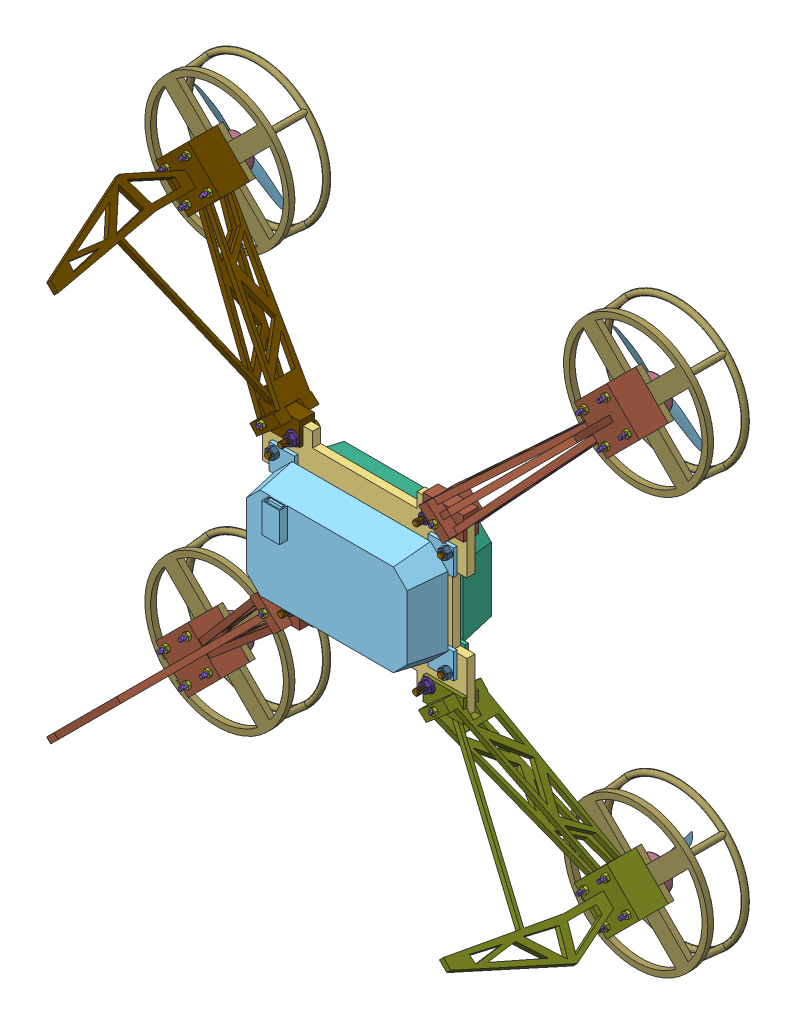
SolidWorks assembly ds2, configuration Default. Lengths in mm.
Overall size (539.99 537.83 191.42).
99 component instances, 18 part files, 83 mates.
Components (placement in the parent):
- battery-1: battery [Default] at (18.8177 46.9585 54.9424) size (80 50 20)
- casing-1: casing [Default] at (19.625 49.8237 64.9424) size (96 66 13)
- frame-1: frame [Default] at (21.8083 42.8166 57.9424) x (0 1 0) z (0 0 1) size (147.04 177.04 7)
- microelectronics-1: microelectronics [Default] at (21.2423 49.2552 77.9424) size (63.91 64.04 8)
- shell-1: shell [Default] at (46.8083 62.2846 67.9424) size (159.85 99.85 47)
- shell up-1: shell up [Default] at (-3.1917 62.2846 54.9424) x (-1 0 0) z (0 0 -1) size (159.85 99.85 36)
- casing-3: casing [Default] at (19.625 35.8094 57.9424) x (1 0 0) z (0 0 -1) size (96 66 13)
- M3 Nut-1: M3 Nut [Default] at (67.2879 12.3183 79.1424) x (0.927238 -0.374472 0) z (0 0 1) size (5.5 6.35 2.74)
- M3 X 16mm Screw-1: M3 X 16mm Screw [Default] at (67.3083 12.3166 71.5424) x (0 0 1) z (-0.987325 -0.158711 0) size (48.24 5.6 5.6)
- M3 Nut-2: M3 Nut [Default] at (-23.6713 12.3183 79.1424) x (-0.927238 -0.374472 0) z (0 0 1) size (5.5 6.35 2.74)
- M3 X 16mm Screw-2: M3 X 16mm Screw [Default] at (-23.6917 12.3166 71.5424) x (0 0 1) z (0.987325 -0.158711 0) size (48.24 5.6 5.6)
- M3 Nut-3: M3 Nut [Default] at (67.2879 73.3148 79.1424) x (0.927238 0.374472 0) z (0 0 1) size (5.5 6.35 2.74)
- M3 X 16mm Screw-3: M3 X 16mm Screw [Default] at (67.3083 73.3166 71.5424) x (0 0 1) z (-0.987325 0.158711 0) size (48.24 5.6 5.6)
- M3 Nut-4: M3 Nut [Default] at (-23.6713 73.3148 79.1424) x (-0.927238 0.374472 0) z (0 0 1) size (5.5 6.35 2.74)
- M3 X 16mm Screw-4: M3 X 16mm Screw [Default] at (-23.6917 73.3166 71.5424) x (0 0 1) z (0.987325 0.158711 0) size (48.24 5.6 5.6)
- heavy hex flange screw_am-1: heavy hex flange screw_am [B18.2.3.9M - Heavy hex flange screw, M5 x 0.8 x 20 --20S] at (-53.1917 87.8166 49.1424) x (0 0 1) z (-0.923728 -0.383049 0) size (25.8 11.8 11.8)
- hex nut style 1_am-1: hex nut style 1_am [B18.2.4.1M - Hex nut, Style 1,  M5 x 0.8 --D-N] at (-53.1917 87.8166 67.9424) x (1 0 0) z (0 0 -1) size (8 9.24 4.7)
- heavy hex flange screw_am-2: heavy hex flange screw_am [B18.2.3.9M - Heavy hex flange screw, M5 x 0.8 x 20 --20S] at (96.8083 87.8166 49.1424) x (0 0 1) z (-0.923728 0.383049 0) size (25.8 11.8 11.8)
- hex nut style 1_am-2: hex nut style 1_am [B18.2.4.1M - Hex nut, Style 1,  M5 x 0.8 --D-N] at (96.8083 87.8166 72.6424) x (-1 0 0) z (0 0 1) size (8 9.24 4.7)
- heavy hex flange screw_am-3: heavy hex flange screw_am [B18.2.3.9M - Heavy hex flange screw, M5 x 0.8 x 20 --20S] at (-53.1917 -2.1834 49.1424) x (0 0 1) z (0.923728 -0.383049 0) size (25.8 11.8 11.8)
- hex nut style 1_am-3: hex nut style 1_am [B18.2.4.1M - Hex nut, Style 1,  M5 x 0.8 --D-N] at (-53.1917 -2.1834 72.6424) size (8 9.24 4.7)
- heavy hex flange screw_am-4: heavy hex flange screw_am [B18.2.3.9M - Heavy hex flange screw, M5 x 0.8 x 20 --20S] at (96.8083 -2.1834 49.1424) x (0 0 1) z (0.923728 0.383049 0) size (25.8 11.8 11.8)
- hex nut style 1_am-4: hex nut style 1_am [B18.2.4.1M - Hex nut, Style 1,  M5 x 0.8 --D-N] at (96.8083 -2.1834 67.9424) x (-1 0 0) z (0 0 -1) size (8 9.24 4.7)
- arms-2: arms [Default] at (-49.2115 -25.7033 61.4424) size (156.23 150.15 153.92)
- propellers-1: propellers [Default] at (-143.0026 -204.8079 -99.2159) x (0.707107 0.707107 0) z (0 0 1) size (125.2 125.2 37.5)
  - propeller shield-1: propeller shield [Default] at (35.7674 59.3211 105.7949) size (125.2 125.2 37.5)
  - motor-1: motor [Default] at (35.7674 59.3211 90.0261) x (1 0 0) z (0 1 0) size (28.43 25 28.43)
  - aeronaut_cam_carbon_light_13x5.step-1: aeronaut_cam_carbon_light_13x5.step [Default] at (35.7659 59.3206 89.8554) x (0.983894 0.178751 0) z (0 0 1) size (100.1 9.42 3.24)
  - M3 Nut-1: M3 Nut [Default] at (35.7674 59.3211 87.1925) x (0.707107 0.707107 0) z (0 0 1) size (5.5 6.35 2.74)
  - tip-2: tip [Default] at (35.7674 59.3211 82.6885) x (-0.916245 0.400617 0) z (-0.400617 -0.916245 0) size (4.73 7 4.73)
- arms-6: arms [Default] at (92.8281 111.3364 61.4424) x (-1 0 0) z (0 0 1) size (156.23 150.15 153.92)
- propellers-4: propellers [Default] at (136.0365 206.5484 -99.2159) x (0.707107 -0.707107 0) z (0 0 1) size (125.2 125.2 37.5)
  - propeller shield-1: propeller shield [Default] at (35.7674 59.3211 105.7949) size (125.2 125.2 37.5)
  - motor-1: motor [Default] at (35.7674 59.3211 90.0261) x (1 0 0) z (0 1 0) size (28.43 25 28.43)
  - aeronaut_cam_carbon_light_13x5.step-1: aeronaut_cam_carbon_light_13x5.step [Default] at (35.7659 59.3206 89.8554) x (0.983894 0.178751 0) z (0 0 1) size (100.1 9.42 3.24)
  - M3 Nut-1: M3 Nut [Default] at (35.7674 59.3211 87.1925) x (0.707107 0.707107 0) z (0 0 1) size (5.5 6.35 2.74)
  - tip-2: tip [Default] at (35.7674 59.3211 82.6885) x (-0.916245 0.400617 0) z (-0.400617 -0.916245 0) size (4.73 7 4.73)
- M3 X 16mm Screw-5: M3 X 16mm Screw [Default] at (-51.8729 -27.4903 71.5424) x (0 0 1) z (-1 0 0) size (48.24 5.6 5.6)
- M3 Nut-5: M3 Nut [Default] at (-51.8729 -27.4903 79.1424) size (5.5 6.35 2.74)
- M3 Nut-6: M3 Nut [Default] at (-159.6576 -119.1854 37.7789) size (5.5 6.35 2.74)
- M3 X 16mm Screw-6: M3 X 16mm Screw [Default] at (-159.6576 -119.1854 33.1789) x (0 0 1) z (-0.923728 -0.383049 0) size (48.24 5.6 5.6)
- M3 X 16mm Screw-7: M3 X 16mm Screw [Default] at (-178.0423 -137.5702 33.1789) x (0 0 1) z (-0.383049 -0.923728 0) size (48.24 5.6 5.6)
- M3 Nut-7: M3 Nut [Default] at (-178.0423 -137.5702 37.7789) x (0 1 0) z (0 0 1) size (5.5 6.35 2.74)
- M3 X 16mm Screw-8: M3 X 16mm Screw [Default] at (-141.2728 -137.5702 33.1789) x (0 0 1) z (0.383049 0.923728 0) size (48.24 5.6 5.6)
- M3 Nut-8: M3 Nut [Default] at (-141.2728 -137.5702 37.7789) x (0 -1 0) z (0 0 1) size (5.5 6.35 2.74)
- M3 X 16mm Screw-9: M3 X 16mm Screw [Default] at (-159.6576 -155.9549 33.1789) x (0 0 1) z (-0.923728 -0.383049 0) size (48.24 5.6 5.6)
- M3 Nut-9: M3 Nut [Default] at (-159.6576 -155.9549 37.7789) size (5.5 6.35 2.74)
- M3 Nut-10: M3 Nut [Default] at (95.4895 113.1235 79.1424) size (5.5 6.35 2.74)
- M3 X 16mm Screw-10: M3 X 16mm Screw [Default] at (95.4895 113.1235 71.5424) x (0 0 1) z (-1 0 0) size (48.24 5.6 5.6)
- M3 Nut-11: M3 Nut [Default] at (203.2742 241.5881 37.7789) size (5.5 6.35 2.74)
- M3 X 16mm Screw-11: M3 X 16mm Screw [Default] at (203.2742 241.5881 33.1789) x (0 0 1) z (-1 0 0) size (48.24 5.6 5.6)
- M3 X 16mm Screw-12: M3 X 16mm Screw [Default] at (221.659 223.2033 33.1789) x (0 0 1) z (0 1 0) size (48.24 5.6 5.6)
- M3 Nut-12: M3 Nut [Default] at (221.659 223.2033 37.7789) x (0 -1 0) z (0 0 1) size (5.5 6.35 2.74)
- M3 X 16mm Screw-13: M3 X 16mm Screw [Default] at (184.8894 223.2033 33.1789) x (0 0 1) z (0 -1 0) size (48.24 5.6 5.6)
- M3 Nut-13: M3 Nut [Default] at (184.8894 223.2033 37.7789) x (0 1 0) z (0 0 1) size (5.5 6.35 2.74)
- M3 X 16mm Screw-14: M3 X 16mm Screw [Default] at (203.2742 204.8185 33.1789) x (0 0 1) z (-1 0 0) size (48.24 5.6 5.6)
- M3 Nut-14: M3 Nut [Default] at (203.2742 204.8185 37.7789) size (5.5 6.35 2.74)
- Mirror1arms-9: Mirror1arms [Default] at (92.8281 -25.7033 61.4424) size (156.23 150.15 153.92)
- propellers-7: propellers [Default] at (219.9284 -204.8072 -99.2159) x (0.707107 0.707107 0) z (0 0 1) size (125.2 125.2 37.5)
  - propeller shield-1: propeller shield [Default] at (35.7674 59.3211 105.7949) size (125.2 125.2 37.5)
  - motor-1: motor [Default] at (35.7674 59.3211 90.0261) x (1 0 0) z (0 1 0) size (28.43 25 28.43)
  - aeronaut_cam_carbon_light_13x5.step-1: aeronaut_cam_carbon_light_13x5.step [Default] at (35.7659 59.3206 89.8554) x (0.983894 0.178751 0) z (0 0 1) size (100.1 9.42 3.24)
  - M3 Nut-1: M3 Nut [Default] at (35.7674 59.3211 87.1925) x (0.707107 0.707107 0) z (0 0 1) size (5.5 6.35 2.74)
  - tip-2: tip [Default] at (35.7674 59.3211 82.6885) x (-0.916245 0.400617 0) z (-0.400617 -0.916245 0) size (4.73 7 4.73)
- M3 Nut-21: M3 Nut [Default] at (-54.004 113.1235 79.1424) x (0.950743 0.309981 0) z (0 0 1) size (5.5 6.35 2.74)
- M3 X 16mm Screw-21: M3 X 16mm Screw [Default] at (-54.004 113.1235 71.5424) x (0 0 1) z (-0.616484 0.787367 0) size (48.24 5.6 5.6)
- M3 Nut-22: M3 Nut [Default] at (95.4895 -27.4903 79.1424) size (5.5 6.35 2.74)
- M3 X 16mm Screw-22: M3 X 16mm Screw [Default] at (95.4895 -27.4903 71.5424) x (0 0 1) z (-0.733154 -0.680063 0) size (48.24 5.6 5.6)
- M3 Nut-23: M3 Nut [Default] at (221.659 -137.5702 37.7789) x (0.996537 0.083147 0) z (0 0 1) size (5.5 6.35 2.74)
- M3 X 16mm Screw-23: M3 X 16mm Screw [Default] at (221.659 -137.5702 33.1789) x (0 0 1) z (-0.99612 -0.088004 0) size (48.24 5.6 5.6)
- M3 X 16mm Screw-24: M3 X 16mm Screw [Default] at (203.2727 -119.1839 33.1789) x (0 0 1) z (0.088004 0.99612 0) size (48.24 5.6 5.6)
- M3 Nut-24: M3 Nut [Default] at (203.2727 -119.1839 37.7789) x (-0.083147 -0.996537 0) z (0 0 1) size (5.5 6.35 2.74)
- M3 X 16mm Screw-25: M3 X 16mm Screw [Default] at (203.2742 -155.9549 33.1789) x (0 0 1) z (-0.088004 -0.99612 0) size (48.24 5.6 5.6)
- M3 Nut-25: M3 Nut [Default] at (203.2742 -155.9549 37.7789) x (0.083147 0.996537 0) z (0 0 1) size (5.5 6.35 2.74)
- M3 X 16mm Screw-26: M3 X 16mm Screw [Default] at (184.8879 -137.5687 33.1789) x (0 0 1) z (-0.99612 -0.088004 0) size (48.24 5.6 5.6)
- M3 Nut-26: M3 Nut [Default] at (184.8879 -137.5687 37.7789) x (0.996537 0.083147 0) z (0 0 1) size (5.5 6.35 2.74)
- heavy hex flange screw_am-6: heavy hex flange screw_am [B18.2.3.9M - Heavy hex flange screw, M5 x 0.8 x 25 --16S] at (-36.7115 -20.7033 49.1424) x (0 0 1) z (-0.981596 -0.190971 0) size (30.8 11.8 11.8)
- heavy hex flange screw_am-7: heavy hex flange screw_am [B18.2.3.9M - Heavy hex flange screw, M5 x 0.8 x 25 --16S] at (-36.7115 106.3364 49.1424) x (0 0 1) z (0.20205 -0.979375 0) size (30.8 11.8 11.8)
- heavy hex flange screw_am-8: heavy hex flange screw_am [B18.2.3.9M - Heavy hex flange screw, M5 x 0.8 x 25 --16S] at (80.3281 -20.7033 49.1424) x (0 0 1) z (-0.923728 -0.383049 0) size (30.8 11.8 11.8)
- heavy hex flange screw_am-9: heavy hex flange screw_am [B18.2.3.9M - Heavy hex flange screw, M5 x 0.8 x 25 --16S] at (80.3281 106.3364 49.1424) x (0 0 1) z (-0.923728 -0.383049 0) size (30.8 11.8 11.8)
- hex flange nut_am-1: hex flange nut_am [B18.2.2.4M - Hex flange nut, M5 x 0.8 --N] at (-36.7115 -20.7033 72.9424) x (-0.923728 -0.383049 0) z (0 0 1) size (11.8 11.8 5)
- hex flange nut_am-2: hex flange nut_am [B18.2.2.4M - Hex flange nut, M5 x 0.8 --N] at (80.3281 -20.7033 72.9424) size (11.8 11.8 5)
- hex flange nut_am-3: hex flange nut_am [B18.2.2.4M - Hex flange nut, M5 x 0.8 --N] at (80.3281 106.3364 72.9424) size (11.8 11.8 5)
- hex flange nut_am-4: hex flange nut_am [B18.2.2.4M - Hex flange nut, M5 x 0.8 --N] at (-36.7115 106.3364 72.9424) size (11.8 11.8 5)
- Mirrorarms1-9: Mirrorarms1 [Default] at (-49.2115 111.3364 61.4424) x (-1 0 0) z (0 0 1) size (156.23 150.15 153.92)
- propellers-8: propellers [Default] at (-92.4198 239.8582 -99.2159) x (-0.707107 0.707107 0) z (0 0 1) size (125.2 125.2 37.5)
  - propeller shield-1: propeller shield [Default] at (35.7674 59.3211 105.7949) size (125.2 125.2 37.5)
  - motor-1: motor [Default] at (35.7674 59.3211 90.0261) x (1 0 0) z (0 1 0) size (28.43 25 28.43)
  - aeronaut_cam_carbon_light_13x5.step-1: aeronaut_cam_carbon_light_13x5.step [Default] at (35.7659 59.3206 89.8554) x (0.983894 0.178751 0) z (0 0 1) size (100.1 9.42 3.24)
  - M3 Nut-1: M3 Nut [Default] at (35.7674 59.3211 87.1925) x (0.707107 0.707107 0) z (0 0 1) size (5.5 6.35 2.74)
  - tip-2: tip [Default] at (35.7674 59.3211 82.6885) x (-0.916245 0.400617 0) z (-0.400617 -0.916245 0) size (4.73 7 4.73)
- M3 Nut-31: M3 Nut [Default] at (-178.0423 223.2033 37.7789) size (5.5 6.35 2.74)
- M3 X 16mm Screw-31: M3 X 16mm Screw [Default] at (-178.0423 223.2033 33.1789) x (0 0 1) z (-0.898713 0.438538 0) size (48.24 5.6 5.6)
- M3 X 16mm Screw-32: M3 X 16mm Screw [Default] at (-159.6576 204.8185 33.1789) x (0 0 1) z (-0.438538 0.898713 0) size (48.24 5.6 5.6)
- M3 Nut-32: M3 Nut [Default] at (-159.6576 204.8185 37.7789) x (0 -1 0) z (0 0 1) size (5.5 6.35 2.74)
- M3 X 16mm Screw-33: M3 X 16mm Screw [Default] at (-159.6576 241.5881 33.1789) x (0 0 1) z (0.438538 -0.898713 0) size (48.24 5.6 5.6)
- M3 Nut-33: M3 Nut [Default] at (-159.6576 241.5881 37.7789) x (0 1 0) z (0 0 1) size (5.5 6.35 2.74)
- M3 X 16mm Screw-34: M3 X 16mm Screw [Default] at (-141.2728 223.2033 33.1789) x (0 0 1) z (-0.898713 0.438538 0) size (48.24 5.6 5.6)
- M3 Nut-34: M3 Nut [Default] at (-141.2728 223.2033 37.7789) size (5.5 6.35 2.74)
Mates (geometry in assembly coordinates):
- Width3: width aligned: plane of battery-1 through (-18.1917 17.7996 74.9424) normal (0 -1 0); plane of battery-1 through (-18.1917 67.7996 74.9424) normal (0 1 0); plane of casing-1 through (-18.1917 67.8166 74.9424) normal (0 -1 0); plane of casing-1 through (61.8083 17.7827 169.455) normal (0 1 0)
- Width4: width anti-aligned: plane of battery-1 through (-18.1917 67.7996 74.9424) normal (-1 0 0); plane of battery-1 through (61.8083 67.7996 74.9424) normal (1 0 0); plane of casing-1 through (64.8083 70.8166 74.9424) normal (1 0 0); plane of casing-1 through (-21.1917 70.8166 74.9424) normal (-1 0 0)
- Width6: width anti-aligned: plane of microelectronics-1 through (-8.1917 72.8166 80.9424) normal (-1 0 0); plane of microelectronics-1 through (51.8083 72.8166 80.9424) normal (1 0 0); plane of casing-1 through (64.8083 70.8166 74.9424) normal (1 0 0); plane of casing-1 through (-21.1917 70.8166 74.9424) normal (-1 0 0)
- Coincident4: coincident anti-aligned: plane of casing-1 through (19.625 49.8237 77.9424) normal (0 0 1); plane of microelectronics-1 through (21.2423 49.2552 77.9424) normal (0 0 -1)
- Coincident5: coincident anti-aligned: plane of battery-1 through (18.8177 46.9585 74.9424) normal (0 0 1); plane of casing-1 through (19.625 49.8237 74.9424) normal (0 0 -1)
- Concentric1: concentric aligned: cylinder of casing-1 through (-23.6917 12.3166 50.8002) axis (0 0 1) radius 1.5; cylinder of frame-1 through (-23.6917 12.3166 54.9424) axis (0 0 1) radius 1.5
- Concentric2: concentric aligned: cylinder of casing-1 through (-23.6917 73.3166 50.8002) axis (0 0 1) radius 1.5; cylinder of frame-1 through (-23.6917 73.3166 54.9424) axis (0 0 1) radius 1.5
- Coincident6: coincident anti-aligned: plane of casing-1 through (19.625 49.8237 64.9424) normal (0 0 -1); plane of frame-1 through (21.8083 42.8166 64.9424) normal (0 0 1)
- Concentric3: concentric anti-aligned: cylinder of casing-3 through (67.3083 12.3166 72.0845) axis (0 0 -1) radius 1.5; cylinder of M3 X 16mm Screw-1 through (67.3083 12.3166 89.9424) axis (0 0 1) radius 1.5
- Coincident7: coincident anti-aligned: plane of casing-3 through (19.625 35.8094 44.9424) normal (0 0 -1); plane of M3 X 16mm Screw-1 through (68.7893 12.5546 44.9424) normal (0 0 1)
- Tangent1: tangent: curve of M3 Nut-1; edge_curve of M3 X 16mm Screw-1
- Coincident8: coincident anti-aligned: plane of casing-1 through (19.625 49.8237 77.9424) normal (0 0 1); plane of M3 Nut-1 through (67.2879 12.3183 77.9424) normal (0 0 -1)
- Coincident11: coincident anti-aligned: plane of frame-1 through (21.8083 42.8166 57.9424) normal (-1 0 0); plane of shell up-1 through (21.8083 62.2846 54.9424) normal (1 0 0)
- Coincident12: coincident aligned: plane of frame-1 through (21.8083 42.8166 57.9424) normal (0 1 0); plane of shell up-1 through (-3.1917 42.8166 54.9424) normal (0 1 0)
- Coincident13: coincident aligned: plane of shell-1 through (46.8083 42.8166 67.9424) normal (0 1 0); plane of shell up-1 through (-3.1917 42.8166 54.9424) normal (0 1 0)
- Coincident14: coincident aligned: plane of shell-1 through (21.8083 62.2846 67.9424) normal (1 0 0); plane of shell up-1 through (21.8083 62.2846 54.9424) normal (1 0 0)
- Coincident15: coincident anti-aligned: plane of frame-1 through (21.8083 42.8166 57.9424) normal (0 0 -1); plane of arms-1 through (58.4404 112.3682 57.9424) normal (0 0 1)
- Coincident16: coincident anti-aligned: plane of frame-1 through (21.8083 42.8166 57.9424) normal (0 0 -1); plane of shell up-1 through (-3.1917 62.2846 57.9424) normal (0 0 1)
- Coincident17: coincident anti-aligned: plane of frame-1 through (21.8083 42.8166 64.9424) normal (0 0 1); plane of shell-1 through (46.8083 23.3485 64.9424) normal (0 0 -1)
- Concentric4: concentric aligned: circle of shell up-1; circle of heavy hex flange screw_am-1
- Coincident18: coincident anti-aligned: plane of shell up-1 through (-3.1917 62.2846 54.9424) normal (0 0 -1); plane of heavy hex flange screw_am-1 through (-54.9609 92.0831 54.9424) normal (0 0 1)
- Concentric5: concentric aligned: circle of heavy hex flange screw_am-1; cylinder of hex nut style 1_am-1 through (-53.1917 87.8166 72.6424) axis (0 0 -1) radius 2.1
- Coincident19: coincident anti-aligned: plane of shell-1 through (46.8083 23.3485 67.9424) normal (0 0 1); plane of hex nut style 1_am-1 through (-61.1917 87.8166 67.9424) normal (0 0 -1)
- Coincident20: coincident anti-aligned: plane of frame-1 through (21.8083 42.8166 57.9424) normal (0 0 -1); plane of arms-2 through (-31.7115 -30.7033 57.9424) normal (0 0 1)
- Coincident21: coincident aligned: plane of frame-1 through (-66.7115 12.5924 64.9424) normal (-1 0 0); plane of arms-2 through (-66.7115 -15.7033 67.9424) normal (-1 0 0)
- Coincident22: coincident anti-aligned: plane of arms-2 through (-49.2115 -25.7033 11.5789) normal (0 0 -1); plane of propellers-1/propeller shield-1 through (-159.6576 -137.5702 11.5789) normal (0 0 1)
- Concentric6: concentric anti-aligned: cylinder of arms-2 through (-159.6576 -155.9549 36.5789) axis (0 0 -1) radius 1.5; cylinder of propellers-1/propeller shield-1 through (-159.6576 -155.9549 -49.9896) axis (0 0 1) radius 1.5
- Concentric7: concentric anti-aligned: cylinder of arms-2 through (-141.2728 -137.5702 36.5789) axis (0 0 -1) radius 1.5; cylinder of propellers-1/propeller shield-1 through (-141.2728 -137.5702 -49.9896) axis (0 0 1) radius 1.5
- Coincident24: coincident anti-aligned: plane of frame-1 through (-23.4159 -30.7033 64.9424) normal (0 -1 0); plane of arms-2 through (-31.7115 -30.7033 57.9424) normal (0 1 0)
- Coincident25: coincident anti-aligned: plane of frame-1 through (21.8083 42.8166 64.9424) normal (0 0 1); plane of arms-6 through (75.3281 116.3364 64.9424) normal (0 0 -1)
- Coincident28: coincident anti-aligned: plane of arms-6 through (92.8281 111.3364 11.5789) normal (0 0 -1); plane of propellers-4/propeller shield-1 through (203.2742 223.2033 11.5789) normal (0 0 1)
- Concentric8: concentric anti-aligned: cylinder of arms-6 through (184.8894 223.2033 36.5789) axis (0 0 -1) radius 1.5; cylinder of propellers-4/propeller shield-1 through (184.8894 223.2033 -49.9896) axis (0 0 1) radius 1.5
- Concentric9: concentric anti-aligned: cylinder of arms-6 through (203.2742 204.8185 36.5789) axis (0 0 -1) radius 1.5; cylinder of propellers-4/propeller shield-1 through (203.2742 204.8185 -49.9896) axis (0 0 1) radius 1.5
- Coincident30: coincident anti-aligned: circle of arms-2; cylinder of M3 X 16mm Screw-5 through (-51.8729 -27.4903 89.9424) axis (0 0 1) radius 1.5
- Coincident31: coincident anti-aligned: plane of arms-2 through (-49.2115 -25.7033 44.9424) normal (0 0 -1); plane of M3 X 16mm Screw-5 through (-50.3729 -27.4903 44.9424) normal (0 0 1)
- Coincident32: coincident anti-aligned: line of M3 X 16mm Screw-5 through (-51.8729 -27.4903 41.4351) axis (0 0 1); line of M3 Nut-5 through (-51.8729 -27.4903 78.7273) axis (0 0 -1)
- Coincident33: coincident anti-aligned: plane of arms-2 through (-49.2115 -25.7033 77.9424) normal (0 0 1); plane of M3 Nut-5 through (-51.8729 -27.4903 77.9424) normal (0 0 -1)
- Coincident34: coincident aligned: line of propellers-1/propeller shield-1 through (-159.6576 -119.1854 6.5789) axis (0 0 1); line of M3 X 16mm Screw-6 through (-159.6576 -119.1854 6.5789) axis (0 0 1)
- Coincident35: coincident anti-aligned: plane of propellers-1/propeller shield-1 through (-159.6576 -137.5702 6.5789) normal (0 0 -1); plane of M3 X 16mm Screw-6 through (-158.272 -118.6108 6.5789) normal (0 0 1)
- Coincident36: coincident anti-aligned: line of M3 Nut-6 through (-159.6576 -119.1854 37.3639) axis (0 0 -1); line of M3 X 16mm Screw-6 through (-159.6576 -119.1854 6.5789) axis (0 0 1)
- Coincident37: coincident anti-aligned: plane of arms-2 through (-49.2115 -25.7033 36.5789) normal (0 0 1); plane of M3 Nut-6 through (-159.6576 -119.1854 36.5789) normal (0 0 -1)
- Coincident40: coincident anti-aligned: plane of frame-1 through (67.0325 116.3364 64.9424) normal (0 1 0); plane of arms-6 through (75.3281 116.3364 57.9424) normal (0 -1 0)
- Coincident41: coincident aligned: plane of frame-1 through (110.3281 73.0408 64.9424) normal (1 0 0); plane of arms-6 through (110.3281 101.3364 67.9424) normal (1 0 0)
- Concentric10: concentric anti-aligned: cylinder of arms-6 through (95.4895 113.1235 77.9424) axis (0 0 -1) radius 1.5; cylinder of M3 X 16mm Screw-10 through (95.4895 113.1235 89.9424) axis (0 0 1) radius 1.5
- Coincident42: coincident anti-aligned: plane of arms-6 through (92.8281 111.3364 44.9424) normal (0 0 -1); plane of M3 X 16mm Screw-10 through (96.9895 113.1235 44.9424) normal (0 0 1)
- Coincident43: coincident aligned: line of arms-6 through (95.4895 113.1235 77.9424) axis (0 0 -1); line of M3 Nut-10 through (95.4895 113.1235 80.0719) axis (0 0 -1)
- Coincident44: coincident anti-aligned: plane of arms-6 through (92.8281 111.3364 77.9424) normal (0 0 1); plane of M3 Nut-10 through (95.4895 113.1235 77.9424) normal (0 0 -1)
- Coincident45: coincident anti-aligned: line of arms-6 through (203.2742 241.5881 36.5789) axis (0 0 -1); line of M3 X 16mm Screw-11 through (203.2742 241.5881 6.5789) axis (0 0 1)
- Coincident47: coincident anti-aligned: plane of propellers-4/propeller shield-1 through (203.2742 223.2033 6.5789) normal (0 0 -1); plane of M3 X 16mm Screw-11 through (204.7742 241.5881 6.5789) normal (0 0 1)
- Coincident48: coincident aligned: line of arms-6 through (203.2742 241.5881 36.5789) axis (0 0 -1); line of M3 Nut-11 through (203.2742 241.5881 38.9789) axis (0 0 -1)
- Coincident49: coincident anti-aligned: plane of arms-6 through (92.8281 111.3364 36.5789) normal (0 0 1); plane of M3 Nut-11 through (203.2742 241.5881 36.5789) normal (0 0 -1)
- Coincident54: coincident anti-aligned: plane of Mirrorarms-10 through (-51.3427 111.3364 77.9424) normal (0 0 1); plane of M3 Nut-21 through (-54.004 113.1235 77.9424) normal (0 0 -1)
- Coincident55: coincident anti-aligned: line of Mirror1arms-9 through (95.4895 -27.4903 57.9424) axis (0 0 -1); line of M3 X 16mm Screw-22 through (95.4895 -27.4903 44.9424) axis (0 0 1)
- Coincident56: coincident anti-aligned: plane of Mirror1arms-9 through (92.8281 -25.7033 44.9424) normal (0 0 -1); circle of M3 X 16mm Screw-22
- Coincident57: coincident aligned: line of M3 Nut-22 through (95.4895 -27.4903 79.5574) axis (0 0 1); line of M3 X 16mm Screw-22 through (95.4895 -27.4903 44.9424) axis (0 0 1)
- Coincident58: coincident anti-aligned: plane of Mirror1arms-9 through (92.8281 -25.7033 77.9424) normal (0 0 1); plane of M3 Nut-22 through (95.4895 -27.4903 77.9424) normal (0 0 -1)
- Coincident59: coincident anti-aligned: line of Mirror1arms-9 through (221.659 -137.5702 36.5789) axis (0 0 -1); line of M3 X 16mm Screw-23 through (221.659 -137.5702 6.5789) axis (0 0 1)
- Coincident60: coincident anti-aligned: line of M3 Nut-23 through (221.659 -137.5702 38.7084) axis (0 0 -1); line of M3 X 16mm Screw-23 through (221.659 -137.5702 6.5789) axis (0 0 1)
- Coincident61: coincident anti-aligned: plane of propellers-7/propeller shield-1 through (203.2734 -137.5694 6.5789) normal (0 0 -1); plane of M3 X 16mm Screw-23 through (223.1531 -137.4382 6.5789) normal (0 0 1)
- Coincident62: coincident anti-aligned: plane of Mirror1arms-9 through (92.8281 -25.7033 36.5789) normal (0 0 1); plane of M3 Nut-23 through (221.659 -137.5702 36.5789) normal (0 0 -1)
- Coincident63: coincident anti-aligned: line of Mirrorarms-10 through (-161.7887 204.8185 36.5789) axis (0 0 -1); line of M3 X 16mm Screw-27 through (-161.7887 204.8185 6.5789) axis (0 0 1)
- Coincident65: coincident anti-aligned: line of M3 Nut-27 through (-161.7887 202.6874 38.7084) axis (0 0 -1); line of M3 X 16mm Screw-27 through (-161.7887 202.6874 6.5789) axis (0 0 1)
- Coincident66: coincident anti-aligned: plane of Mirrorarms-10 through (-51.3427 111.3364 36.5789) normal (0 0 1); plane of M3 Nut-27 through (-161.7887 202.6874 36.5789) normal (0 0 -1)
- Concentric11: concentric aligned: cylinder of arms-2 through (-36.7115 -20.7033 165.5015) axis (0 0 -1) radius 2.5; cylinder of heavy hex flange screw_am-6 through (-36.7115 -20.7033 49.1424) axis (0 0 -1) radius 2.5
- Coincident67: coincident anti-aligned: plane of arms-2 through (-49.2115 -25.7033 54.9424) normal (0 0 -1); plane of heavy hex flange screw_am-6 through (-37.5936 -16.1695 54.9424) normal (0 0 1)
- Concentric12: concentric anti-aligned: circle of heavy hex flange screw_am-6; cylinder of hex flange nut_am-1 through (-36.7115 -20.7033 67.9424) axis (0 0 1) radius 2.1
- Coincident68: coincident anti-aligned: plane of arms-2 through (-49.2115 -25.7033 67.9424) normal (0 0 1); plane of hex flange nut_am-1 through (-34.9423 -24.9698 67.9424) normal (0 0 -1)
- Coincident85: coincident anti-aligned: line of Mirrorarms1-9 through (-178.0423 223.2033 36.5789) axis (0 0 -1); line of M3 X 16mm Screw-31 through (-178.0423 223.2033 6.5789) axis (0 0 1)
- Coincident86: coincident anti-aligned: plane of propellers-8/propeller shield-1 through (-159.6576 223.2033 6.5789) normal (0 0 -1); plane of M3 X 16mm Screw-31 through (-176.6943 222.5455 6.5789) normal (0 0 1)
- Coincident87: coincident anti-aligned: line of M3 Nut-31 through (-178.0423 223.2033 38.7084) axis (0 0 -1); line of M3 X 16mm Screw-31 through (-178.0423 223.2033 6.5789) axis (0 0 1)
- Coincident88: coincident anti-aligned: plane of Mirrorarms1-9 through (-49.2115 111.3364 36.5789) normal (0 0 1); plane of M3 Nut-31 through (-178.0423 223.2033 36.5789) normal (0 0 -1)
- Coincident89: coincident: line of heavy hex flange screw_am-7 through (-36.7115 106.3364 57.7855) axis (0 0 -1); line of Mirrorarms1-9 through (-36.7115 106.3364 57.9424) axis (0 0 -1)
- Coincident90: coincident anti-aligned: plane of heavy hex flange screw_am-7 through (-41.2351 105.4032 54.9424) normal (0 0 1); plane of Mirrorarms1-9 through (-49.2115 111.3364 54.9424) normal (0 0 -1)
- Coincident91: coincident anti-aligned: line of heavy hex flange screw_am-7 through (-36.7115 106.3364 63.6308) axis (0 0 -1); line of hex flange nut_am-4 through (-36.7115 106.3364 68.2479) axis (0 0 1)
- Coincident92: coincident anti-aligned: plane of hex flange nut_am-4 through (-36.7115 110.9552 67.9424) normal (0 0 -1); plane of Mirrorarms1-9 through (-49.2115 111.3364 67.9424) normal (0 0 1)
- Coincident93: coincident aligned: line of frame-1 through (80.3281 106.3364 64.9424) axis (0 0 -1); line of heavy hex flange screw_am-9 through (80.3281 106.3364 63.6308) axis (0 0 -1)
- Coincident94: coincident anti-aligned: plane of arms-6 through (92.8281 111.3364 54.9424) normal (0 0 -1); plane of heavy hex flange screw_am-9 through (78.5589 110.6029 54.9424) normal (0 0 1)
- Coincident95: coincident anti-aligned: line of arms-6 through (80.3281 106.3364 67.9424) axis (0 0 -1); line of hex flange nut_am-3 through (80.3281 106.3364 68.2479) axis (0 0 1)
- Coincident96: coincident anti-aligned: plane of arms-6 through (92.8281 111.3364 67.9424) normal (0 0 1); plane of hex flange nut_am-3 through (80.3281 110.9552 67.9424) normal (0 0 -1)
- Coincident97: coincident aligned: line of Mirror1arms-9 through (80.3281 -20.7033 67.9424) axis (0 0 -1); line of heavy hex flange screw_am-8 through (80.3281 -20.7033 63.6308) axis (0 0 -1)
- Coincident98: coincident anti-aligned: plane of Mirror1arms-9 through (92.8281 -25.7033 54.9424) normal (0 0 -1); plane of heavy hex flange screw_am-8 through (78.5589 -16.4367 54.9424) normal (0 0 1)
- Coincident99: coincident anti-aligned: line of heavy hex flange screw_am-8 through (80.3281 -20.7033 63.6308) axis (0 0 -1); line of hex flange nut_am-2 through (80.3281 -20.7033 68.2479) axis (0 0 1)
- Coincident100: coincident anti-aligned: plane of Mirror1arms-9 through (92.8281 -25.7033 67.9424) normal (0 0 1); plane of hex flange nut_am-2 through (80.3281 -16.0845 67.9424) normal (0 0 -1)
